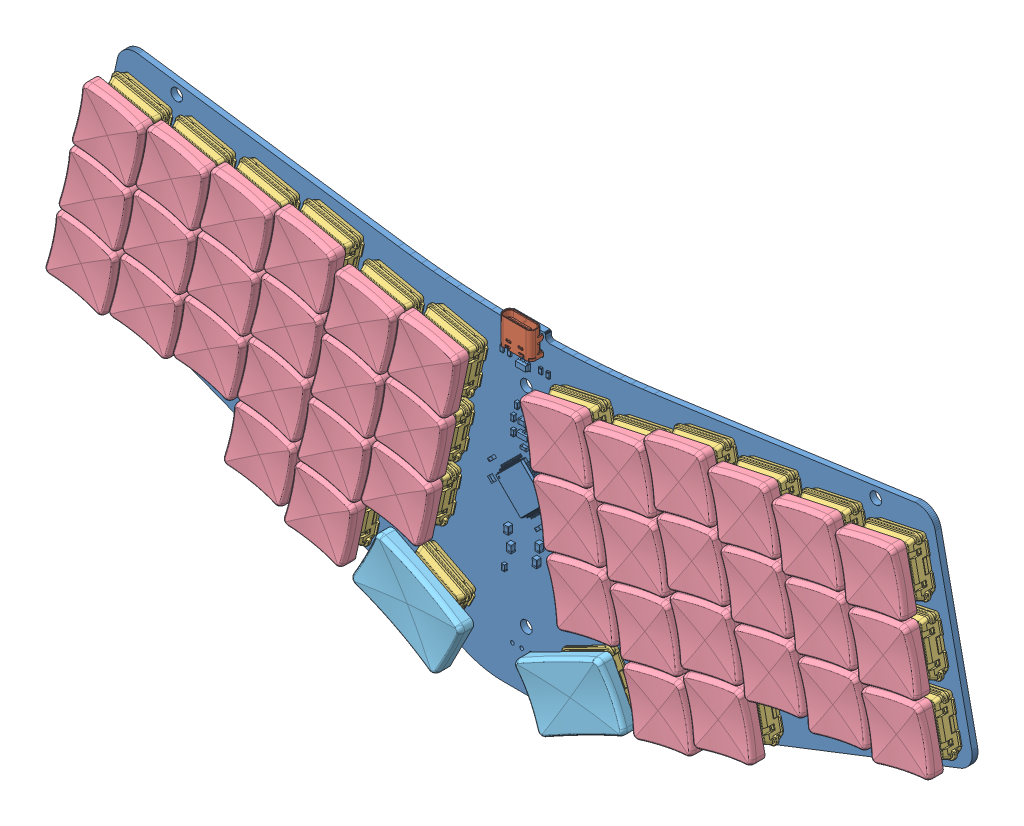
SolidWorks assembly pcb, configuration Default. Lengths in mm.
Overall size (242.52 98.19 15.02).
86 component instances, 5 part files, 216 mates.
Components (placement in the parent):
- pcb_base-1: pcb_base [Default] at (-103.1831 232.8514 177.6164) size (242.52 98.19 4.48)
- usb_c_connector-2: usb_c_connector [Default] at (101.2969 172.9514 179.2464) x (-1 0 0) z (0 0 1) size (8.95 7.9 4.2)
- kailh_choc_switch-1: kailh_choc_switch [Default] at (-6.8998 168.7135 181.3922) x (0.978148 -0.207912 0) z (0 0 1) size (15 15 11)
- kailh_choc_switch-2: kailh_choc_switch [Default] at (-10.4862 151.8404 181.3922) x (0.978148 -0.207912 0) z (0 0 1) size (15 15 11)
- kailh_choc_switch-3: kailh_choc_switch [Default] at (10.3891 167.0833 181.3922) x (0.978148 -0.207912 0) z (0 0 1) size (15 15 11)
- kailh_choc_switch-4: kailh_choc_switch [Default] at (6.8026 150.2102 181.3922) x (0.978148 -0.207912 0) z (0 0 1) size (15 15 11)
- kailh_choc_switch-5: kailh_choc_switch [Default] at (-14.0727 134.9674 181.3922) x (0.978148 -0.207912 0) z (0 0 1) size (15 15 11)
- kailh_choc_switch-6: kailh_choc_switch [Default] at (3.2162 133.3372 181.3922) x (0.978148 -0.207912 0) z (0 0 1) size (15 15 11)
- kailh_choc_switch-7: kailh_choc_switch [Default] at (27.7819 165.9422 181.3922) x (0.978148 -0.207912 0) z (0 0 1) size (15 15 11)
- kailh_choc_switch-8: kailh_choc_switch [Default] at (24.1955 149.0691 181.3922) x (0.978148 -0.207912 0) z (0 0 1) size (15 15 11)
- kailh_choc_switch-9: kailh_choc_switch [Default] at (20.609 132.1961 181.3922) x (0.978148 -0.207912 0) z (0 0 1) size (15 15 11)
- kailh_choc_switch-10: kailh_choc_switch [Default] at (34.4153 114.1819 181.3922) x (0.978148 -0.207912 0) z (0 0 1) size (15 15 11)
- kailh_choc_switch-11: kailh_choc_switch [Default] at (38.0018 131.055 181.3922) x (0.978148 -0.207912 0) z (0 0 1) size (15 15 11)
- kailh_choc_switch-12: kailh_choc_switch [Default] at (41.5883 147.928 181.3922) x (0.978148 -0.207912 0) z (0 0 1) size (15 15 11)
- kailh_choc_switch-13: kailh_choc_switch [Default] at (45.1748 164.8011 181.3922) x (0.978148 -0.207912 0) z (0 0 1) size (15 15 11)
- kailh_choc_switch-14: kailh_choc_switch [Default] at (50.7686 108.1501 181.3922) x (0.978148 -0.207912 0) z (0 0 1) size (15 15 11)
- kailh_choc_switch-15: kailh_choc_switch [Default] at (54.3551 125.0231 181.3922) x (0.978148 -0.207912 0) z (0 0 1) size (15 15 11)
- kailh_choc_switch-16: kailh_choc_switch [Default] at (57.9415 141.8962 181.3922) x (0.978148 -0.207912 0) z (0 0 1) size (15 15 11)
- kailh_choc_switch-17: kailh_choc_switch [Default] at (61.528 158.7692 181.3922) x (0.978148 -0.207912 0) z (0 0 1) size (15 15 11)
- kailh_choc_switch-18: kailh_choc_switch [Default] at (78.8169 157.139 181.3922) x (0.978148 -0.207912 0) z (0 0 1) size (15 15 11)
- kailh_choc_switch-19: kailh_choc_switch [Default] at (75.2304 140.266 181.3922) x (0.978148 -0.207912 0) z (0 0 1) size (15 15 11)
- kailh_choc_switch-20: kailh_choc_switch [Default] at (71.6439 123.3929 181.3922) x (0.978148 -0.207912 0) z (0 0 1) size (15 15 11)
- kailh_choc_switch-21: kailh_choc_switch [Default] at (74.6872 99.2323 181.3922) x (0.891007 -0.45399 0) z (0 0 1) size (15 15 11)
- kailh_choc_switch-22: kailh_choc_switch [Default] at (118.9466 99.2323 181.3922) x (0.891007 0.45399 0) z (0 0 1) size (15 15 11)
- kailh_choc_switch-23: kailh_choc_switch [Default] at (121.9898 123.3929 181.3922) x (0.978148 0.207912 0) z (0 0 1) size (15 15 11)
- kailh_choc_switch-24: kailh_choc_switch [Default] at (118.4034 140.266 181.3922) x (0.978148 0.207912 0) z (0 0 1) size (15 15 11)
- kailh_choc_switch-25: kailh_choc_switch [Default] at (114.8169 157.139 181.3922) x (0.978148 0.207912 0) z (0 0 1) size (15 15 11)
- kailh_choc_switch-26: kailh_choc_switch [Default] at (142.8652 108.1501 181.3922) x (0.978148 0.207912 0) z (0 0 1) size (15 15 11)
- kailh_choc_switch-27: kailh_choc_switch [Default] at (139.2787 125.0231 181.3922) x (0.978148 0.207912 0) z (0 0 1) size (15 15 11)
- kailh_choc_switch-28: kailh_choc_switch [Default] at (135.6922 141.8962 181.3922) x (0.978148 0.207912 0) z (0 0 1) size (15 15 11)
- kailh_choc_switch-29: kailh_choc_switch [Default] at (132.1058 158.7692 181.3922) x (0.978148 0.207912 0) z (0 0 1) size (15 15 11)
- kailh_choc_switch-30: kailh_choc_switch [Default] at (159.2185 114.1819 181.3922) x (0.978148 0.207912 0) z (0 0 1) size (15 15 11)
- kailh_choc_switch-31: kailh_choc_switch [Default] at (155.632 131.055 181.3922) x (0.978148 0.207912 0) z (0 0 1) size (15 15 11)
- kailh_choc_switch-32: kailh_choc_switch [Default] at (152.0455 147.928 181.3922) x (0.978148 0.207912 0) z (0 0 1) size (15 15 11)
- kailh_choc_switch-33: kailh_choc_switch [Default] at (148.459 164.8011 181.3922) x (0.978148 0.207912 0) z (0 0 1) size (15 15 11)
- kailh_choc_switch-34: kailh_choc_switch [Default] at (173.0248 132.1961 181.3922) x (0.978148 0.207912 0) z (0 0 1) size (15 15 11)
- kailh_choc_switch-35: kailh_choc_switch [Default] at (169.4383 149.0691 181.3922) x (0.978148 0.207912 0) z (0 0 1) size (15 15 11)
- kailh_choc_switch-36: kailh_choc_switch [Default] at (165.8519 165.9422 181.3922) x (0.978148 0.207912 0) z (0 0 1) size (15 15 11)
- kailh_choc_switch-37: kailh_choc_switch [Default] at (190.4176 133.3372 181.3922) x (0.978148 0.207912 0) z (0 0 1) size (15 15 11)
- kailh_choc_switch-38: kailh_choc_switch [Default] at (186.8312 150.2102 181.3922) x (0.978148 0.207912 0) z (0 0 1) size (15 15 11)
- kailh_choc_switch-39: kailh_choc_switch [Default] at (183.2447 167.0833 181.3922) x (0.978148 0.207912 0) z (0 0 1) size (15 15 11)
- kailh_choc_switch-40: kailh_choc_switch [Default] at (207.7065 134.9674 181.3922) x (0.978148 0.207912 0) z (0 0 1) size (15 15 11)
- kailh_choc_switch-41: kailh_choc_switch [Default] at (204.12 151.8404 181.3922) x (0.978148 0.207912 0) z (0 0 1) size (15 15 11)
- kailh_choc_switch-42: kailh_choc_switch [Default] at (200.5336 168.7135 181.3922) x (0.978148 0.207912 0) z (0 0 1) size (15 15 11)
- 1U-keycap-1: 1U-keycap [Default] at (-16.6848 162.359 186.1922) x (0.978148 -0.207912 0) z (-0.207912 -0.978148 0) size (16.7 6.52 16.7)
- 1U-keycap-2: 1U-keycap [Default] at (-20.2712 145.486 186.1922) x (0.978148 -0.207912 0) z (-0.207912 -0.978148 0) size (16.7 6.52 16.7)
- 1U-keycap-3: 1U-keycap [Default] at (-23.8577 128.6129 186.1922) x (0.978148 -0.207912 0) z (-0.207912 -0.978148 0) size (16.7 6.52 16.7)
- 1U-keycap-4: 1U-keycap [Default] at (0.6041 160.7288 186.1922) x (0.978148 -0.207912 0) z (-0.207912 -0.978148 0) size (16.7 6.52 16.7)
- 1.5U-keycap-1: 1.5U-keycap [Default] at (59.3586 97.7833 186.1922) x (0.891007 -0.45399 0) z (-0.45399 -0.891007 0) size (26.46 7.52 16.96)
- 1U-keycap-5: 1U-keycap [Default] at (40.9836 101.7956 186.1922) x (0.978148 -0.207912 0) z (-0.207912 -0.978148 0) size (16.7 6.52 16.7)
- 1U-keycap-6: 1U-keycap [Default] at (24.6303 107.8275 186.1922) x (0.978148 -0.207912 0) z (-0.207912 -0.978148 0) size (16.7 6.52 16.7)
- 1U-keycap-7: 1U-keycap [Default] at (44.5701 118.6687 186.1922) x (0.978148 -0.207912 0) z (-0.207912 -0.978148 0) size (16.7 6.52 16.7)
- 1U-keycap-8: 1U-keycap [Default] at (61.859 117.0385 186.1922) x (0.978148 -0.207912 0) z (-0.207912 -0.978148 0) size (16.7 6.52 16.7)
- 1U-keycap-9: 1U-keycap [Default] at (69.0319 150.7846 186.1922) x (0.978148 -0.207912 0) z (-0.207912 -0.978148 0) size (16.7 6.52 16.7)
- 1U-keycap-10: 1U-keycap [Default] at (31.8033 141.5736 186.1922) x (0.978148 -0.207912 0) z (-0.207912 -0.978148 0) size (16.7 6.52 16.7)
- 1.5U-keycap-2: 1.5U-keycap [Default] at (111.109 85.9796 186.1922) x (0.891007 0.45399 0) z (0.45399 -0.891007 0) size (26.46 7.52 16.96)
- 1U-keycap-11: 1U-keycap [Default] at (136.5107 98.3651 186.1922) x (0.978148 0.207912 0) z (0.207912 -0.978148 0) size (16.7 6.52 16.7)
- 1U-keycap-14: 1U-keycap [Default] at (108.4624 147.3541 186.1922) x (0.978148 0.207912 0) z (0.207912 -0.978148 0) size (16.7 6.52 16.7)
- 1U-keycap-15: 1U-keycap [Default] at (194.1791 158.9285 186.1922) x (0.978148 0.207912 0) z (0.207912 -0.978148 0) size (16.7 6.52 16.7)
- 1U-keycap-16: 1U-keycap [Default] at (201.3521 125.1824 186.1922) x (0.978148 0.207912 0) z (0.207912 -0.978148 0) size (16.7 6.52 16.7)
- 1U-keycap-17: 1U-keycap [Default] at (166.6704 122.4111 186.1922) x (0.978148 0.207912 0) z (0.207912 -0.978148 0) size (16.7 6.52 16.7)
- 1U-keycap-18: 1U-keycap [Default] at (-2.9824 143.8558 186.1922) x (0.978148 -0.207912 0) z (-0.207912 -0.978148 0) size (16.7 6.52 16.7)
- 1U-keycap-19: 1U-keycap [Default] at (-6.5688 126.9827 186.1922) x (0.978148 -0.207912 0) z (-0.207912 -0.978148 0) size (16.7 6.52 16.7)
- 1U-keycap-20: 1U-keycap [Default] at (17.9969 159.5877 186.1922) x (0.978148 -0.207912 0) z (-0.207912 -0.978148 0) size (16.7 6.52 16.7)
- 1U-keycap-21: 1U-keycap [Default] at (14.4105 142.7147 186.1922) x (0.978148 -0.207912 0) z (-0.207912 -0.978148 0) size (16.7 6.52 16.7)
- 1U-keycap-22: 1U-keycap [Default] at (10.824 125.8416 186.1922) x (0.978148 -0.207912 0) z (-0.207912 -0.978148 0) size (16.7 6.52 16.7)
- 1U-keycap-23: 1U-keycap [Default] at (28.2168 124.7005 186.1922) x (0.978148 -0.207912 0) z (-0.207912 -0.978148 0) size (16.7 6.52 16.7)
- 1U-keycap-24: 1U-keycap [Default] at (35.3898 158.4466 186.1922) x (0.978148 -0.207912 0) z (-0.207912 -0.978148 0) size (16.7 6.52 16.7)
- 1U-keycap-25: 1U-keycap [Default] at (51.743 152.4148 186.1922) x (0.978148 -0.207912 0) z (-0.207912 -0.978148 0) size (16.7 6.52 16.7)
- 1U-keycap-26: 1U-keycap [Default] at (48.1566 135.5417 186.1922) x (0.978148 -0.207912 0) z (-0.207912 -0.978148 0) size (16.7 6.52 16.7)
- 1U-keycap-27: 1U-keycap [Default] at (65.4454 133.9115 186.1922) x (0.978148 -0.207912 0) z (-0.207912 -0.978148 0) size (16.7 6.52 16.7)
- 1U-keycap-28: 1U-keycap [Default] at (112.0489 130.481 186.1922) x (0.978148 0.207912 0) z (0.207912 -0.978148 0) size (16.7 6.52 16.7)
- 1U-keycap-29: 1U-keycap [Default] at (115.6354 113.608 186.1922) x (0.978148 0.207912 0) z (0.207912 -0.978148 0) size (16.7 6.52 16.7)
- 1U-keycap-30: 1U-keycap [Default] at (125.7513 148.9842 186.1922) x (0.978148 0.207912 0) z (0.207912 -0.978148 0) size (16.7 6.52 16.7)
- 1U-keycap-31: 1U-keycap [Default] at (129.3378 132.1112 186.1922) x (0.978148 0.207912 0) z (0.207912 -0.978148 0) size (16.7 6.52 16.7)
- 1U-keycap-32: 1U-keycap [Default] at (132.9243 115.2381 186.1922) x (0.978148 0.207912 0) z (0.207912 -0.978148 0) size (16.7 6.52 16.7)
- 1U-keycap-33: 1U-keycap [Default] at (142.1046 155.0161 186.1922) x (0.978148 0.207912 0) z (0.207912 -0.978148 0) size (16.7 6.52 16.7)
- 1U-keycap-34: 1U-keycap [Default] at (145.6911 138.143 186.1922) x (0.978148 0.207912 0) z (0.207912 -0.978148 0) size (16.7 6.52 16.7)
- 1U-keycap-35: 1U-keycap [Default] at (149.2775 121.27 186.1922) x (0.978148 0.207912 0) z (0.207912 -0.978148 0) size (16.7 6.52 16.7)
- 1U-keycap-36: 1U-keycap [Default] at (152.864 104.3969 186.1922) x (0.978148 0.207912 0) z (0.207912 -0.978148 0) size (16.7 6.52 16.7)
- 1U-keycap-37: 1U-keycap [Default] at (159.4974 156.1572 186.1922) x (0.978148 0.207912 0) z (0.207912 -0.978148 0) size (16.7 6.52 16.7)
- 1U-keycap-38: 1U-keycap [Default] at (163.0839 139.2841 186.1922) x (0.978148 0.207912 0) z (0.207912 -0.978148 0) size (16.7 6.52 16.7)
- 1U-keycap-39: 1U-keycap [Default] at (184.0632 123.5522 186.1922) x (0.978148 0.207912 0) z (0.207912 -0.978148 0) size (16.7 6.52 16.7)
- 1U-keycap-40: 1U-keycap [Default] at (180.4767 140.4252 186.1922) x (0.978148 0.207912 0) z (0.207912 -0.978148 0) size (16.7 6.52 16.7)
- 1U-keycap-41: 1U-keycap [Default] at (176.8902 157.2983 186.1922) x (0.978148 0.207912 0) z (0.207912 -0.978148 0) size (16.7 6.52 16.7)
- 1U-keycap-42: 1U-keycap [Default] at (197.7656 142.0554 186.1922) x (0.978148 0.207912 0) z (0.207912 -0.978148 0) size (16.7 6.52 16.7)
Mates (geometry in assembly coordinates):
- Concentric8: concentric aligned: cylinder of pcb_base-1 through (99.7169 166.7014 176.8264) axis (0 0 1) radius 0.325; cylinder of usb_c_connector-2 through (99.7169 166.7014 179.2464) axis (0 0 1) radius 0.25
- Coincident1: coincident anti-aligned: plane of pcb_base-1 through (96.8169 139.9659 179.1964) normal (0 0 1); plane of usb_c_connector-2 through (94.4769 165.5464 179.1964) normal (0 0 -1)
- Concentric17: concentric anti-aligned: circle of pcb_base-1; circle of kailh_choc_switch-1
- Coincident11: coincident anti-aligned: plane of pcb_base-1 through (96.8169 139.9659 179.1964) normal (0 0 1); plane of kailh_choc_switch-1 through (-1.5081 163.6607 179.1964) normal (0 0 -1)
- Concentric24: concentric: circle of pcb_base-1; circle of kailh_choc_switch-2
- Coincident12: coincident: plane of pcb_base-1 through (96.8169 139.9659 179.1964) normal (0 0 1); plane of kailh_choc_switch-2 through (-5.0946 146.7877 179.1964) normal (0 0 -1)
- Concentric25: concentric anti-aligned: circle of pcb_base-1; circle of kailh_choc_switch-3
- Coincident13: coincident anti-aligned: plane of pcb_base-1 through (96.8169 139.9659 179.1964) normal (0 0 1); plane of kailh_choc_switch-3 through (15.7807 162.0306 179.1964) normal (0 0 -1)
- Concentric26: concentric: circle of pcb_base-1; circle of kailh_choc_switch-4
- Coincident15: coincident: plane of pcb_base-1 through (96.8169 139.9659 179.1964) normal (0 0 1); plane of kailh_choc_switch-4 through (12.1943 145.1575 179.1964) normal (0 0 -1)
- Angle1: planar angle = 0.20944 rad aligned: plane of kailh_choc_switch-1 through (-1.5741 169.8848 186.9922) normal (0.207912 0.978148 0); plane of pcb_base-1 through (92.0669 171.5153 177.6164) normal (0 1 0)
- Angle2: planar angle = 0.20944 rad aligned: plane of kailh_choc_switch-2 through (-5.1606 153.0118 186.9922) normal (0.207912 0.978148 0); plane of pcb_base-1 through (92.0669 171.5153 177.6164) normal (0 1 0)
- Angle3: planar angle = 0.20944 rad aligned: plane of kailh_choc_switch-3 through (15.7148 168.2547 186.9922) normal (0.207912 0.978148 0); plane of pcb_base-1 through (92.0669 171.5153 177.6164) normal (0 1 0)
- Angle4: planar angle = 0.20944 rad aligned: plane of kailh_choc_switch-4 through (12.1283 151.3816 186.9922) normal (0.207912 0.978148 0); plane of pcb_base-1 through (92.0669 171.5153 177.6164) normal (0 1 0)
- Concentric27: concentric anti-aligned: cylinder of pcb_base-1 through (-14.0727 134.9674 176.8264) axis (0 0 1) radius 1.7145; circle of kailh_choc_switch-5
- Coincident20: coincident anti-aligned: plane of pcb_base-1 through (96.8169 139.9659 179.1964) normal (0 0 1); plane of kailh_choc_switch-5 through (-8.6811 129.9146 179.1964) normal (0 0 -1)
- Angle5: planar angle = 0.20944 rad aligned: plane of kailh_choc_switch-5 through (-8.747 136.1387 186.9922) normal (0.207912 0.978148 0); plane of pcb_base-1 through (92.0669 171.5153 177.6164) normal (0 1 0)
- Concentric28: concentric anti-aligned: cylinder of pcb_base-1 through (3.2162 133.3372 176.8264) axis (0 0 1) radius 1.7145; circle of kailh_choc_switch-6
- Concentric29: concentric anti-aligned: cylinder of pcb_base-1 through (20.609 132.1961 176.8264) axis (0 0 1) radius 1.7145; circle of kailh_choc_switch-9
- Concentric30: concentric anti-aligned: cylinder of pcb_base-1 through (24.1955 149.0691 176.8264) axis (0 0 1) radius 1.7145; circle of kailh_choc_switch-8
- Concentric31: concentric: cylinder of pcb_base-1 through (27.7819 165.9422 176.8264) axis (0 0 1) radius 1.7145; circle of kailh_choc_switch-7
- Coincident22: coincident anti-aligned: plane of pcb_base-1 through (96.8169 139.9659 179.1964) normal (0 0 1); plane of kailh_choc_switch-6 through (8.6078 128.2845 179.1964) normal (0 0 -1)
- Coincident23: coincident anti-aligned: plane of pcb_base-1 through (96.8169 139.9659 179.1964) normal (0 0 1); plane of kailh_choc_switch-9 through (26.0006 127.1434 179.1964) normal (0 0 -1)
- Coincident24: coincident anti-aligned: plane of pcb_base-1 through (96.8169 139.9659 179.1964) normal (0 0 1); plane of kailh_choc_switch-8 through (29.5871 144.0164 179.1964) normal (0 0 -1)
- Coincident25: coincident: plane of pcb_base-1 through (96.8169 139.9659 179.1964) normal (0 0 1); plane of kailh_choc_switch-7 through (33.1736 160.8894 179.1964) normal (0 0 -1)
- Angle6: planar angle = 0.20944 rad aligned: plane of kailh_choc_switch-6 through (8.5418 134.5086 186.9922) normal (0.207912 0.978148 0); plane of pcb_base-1 through (92.0669 171.5153 177.6164) normal (0 1 0)
- Angle7: planar angle = 0.20944 rad aligned: plane of kailh_choc_switch-9 through (25.9347 133.3675 186.9922) normal (0.207912 0.978148 0); plane of pcb_base-1 through (92.0669 171.5153 177.6164) normal (0 1 0)
- Angle8: planar angle = 0.20944 rad aligned: plane of kailh_choc_switch-8 through (29.5211 150.2405 186.9922) normal (0.207912 0.978148 0); plane of pcb_base-1 through (92.0669 171.5153 177.6164) normal (0 1 0)
- Angle9: planar angle = 0.20944 rad aligned: plane of kailh_choc_switch-7 through (33.1076 167.1135 186.9922) normal (0.207912 0.978148 0); plane of pcb_base-1 through (92.0669 171.5153 177.6164) normal (0 1 0)
- Concentric32: concentric anti-aligned: cylinder of pcb_base-1 through (34.4153 114.1819 176.8264) axis (0 0 1) radius 1.7145; circle of kailh_choc_switch-10
- Concentric33: concentric anti-aligned: cylinder of pcb_base-1 through (38.0018 131.055 176.8264) axis (0 0 1) radius 1.7145; circle of kailh_choc_switch-11
- Concentric34: concentric anti-aligned: cylinder of pcb_base-1 through (41.5883 147.928 176.8264) axis (0 0 1) radius 1.7145; circle of kailh_choc_switch-12
- Concentric35: concentric: cylinder of pcb_base-1 through (45.1748 164.8011 176.8264) axis (0 0 1) radius 1.7145; circle of kailh_choc_switch-13
- Coincident30: coincident anti-aligned: plane of pcb_base-1 through (96.8169 139.9659 179.1964) normal (0 0 1); plane of kailh_choc_switch-10 through (39.807 109.1292 179.1964) normal (0 0 -1)
- Coincident31: coincident anti-aligned: plane of pcb_base-1 through (96.8169 139.9659 179.1964) normal (0 0 1); plane of kailh_choc_switch-11 through (43.3934 126.0022 179.1964) normal (0 0 -1)
- Coincident32: coincident anti-aligned: plane of pcb_base-1 through (96.8169 139.9659 179.1964) normal (0 0 1); plane of kailh_choc_switch-12 through (46.9799 142.8753 179.1964) normal (0 0 -1)
- Coincident33: coincident: plane of pcb_base-1 through (96.8169 139.9659 179.1964) normal (0 0 1); plane of kailh_choc_switch-13 through (50.5664 159.7483 179.1964) normal (0 0 -1)
- Angle10: planar angle = 0.20944 rad aligned: plane of kailh_choc_switch-10 through (39.741 115.3533 186.9922) normal (0.207912 0.978148 0); plane of pcb_base-1 through (92.0669 171.5153 177.6164) normal (0 1 0)
- Angle11: planar angle = 0.20944 rad aligned: plane of kailh_choc_switch-11 through (43.3275 132.2263 186.9922) normal (0.207912 0.978148 0); plane of pcb_base-1 through (92.0669 171.5153 177.6164) normal (0 1 0)
- Angle12: planar angle = 0.20944 rad aligned: plane of kailh_choc_switch-12 through (46.914 149.0994 186.9922) normal (0.207912 0.978148 0); plane of pcb_base-1 through (92.0669 171.5153 177.6164) normal (0 1 0)
- Angle13: planar angle = 0.20944 rad aligned: plane of kailh_choc_switch-13 through (50.5004 165.9724 186.9922) normal (0.207912 0.978148 0); plane of pcb_base-1 through (92.0669 171.5153 177.6164) normal (0 1 0)
- Concentric36: concentric anti-aligned: cylinder of pcb_base-1 through (50.7686 108.1501 176.8264) axis (0 0 1) radius 1.7145; circle of kailh_choc_switch-14
- Concentric37: concentric anti-aligned: cylinder of pcb_base-1 through (54.3551 125.0231 176.8264) axis (0 0 1) radius 1.7145; circle of kailh_choc_switch-15
- Concentric38: concentric anti-aligned: cylinder of pcb_base-1 through (57.9415 141.8962 176.8264) axis (0 0 1) radius 1.7145; circle of kailh_choc_switch-16
- Concentric39: concentric: cylinder of pcb_base-1 through (61.528 158.7692 176.8264) axis (0 0 1) radius 1.7145; circle of kailh_choc_switch-17
- Coincident38: coincident anti-aligned: plane of pcb_base-1 through (96.8169 139.9659 179.1964) normal (0 0 1); plane of kailh_choc_switch-14 through (56.1602 103.0974 179.1964) normal (0 0 -1)
- Coincident39: coincident anti-aligned: plane of pcb_base-1 through (96.8169 139.9659 179.1964) normal (0 0 1); plane of kailh_choc_switch-15 through (59.7467 119.9704 179.1964) normal (0 0 -1)
- Coincident40: coincident anti-aligned: plane of pcb_base-1 through (96.8169 139.9659 179.1964) normal (0 0 1); plane of kailh_choc_switch-16 through (63.3332 136.8434 179.1964) normal (0 0 -1)
- Coincident41: coincident: plane of pcb_base-1 through (96.8169 139.9659 179.1964) normal (0 0 1); plane of kailh_choc_switch-17 through (66.9197 153.7165 179.1964) normal (0 0 -1)
- Angle14: planar angle = 0.20944 rad aligned: plane of kailh_choc_switch-14 through (56.0943 109.3215 186.9922) normal (0.207912 0.978148 0); plane of pcb_base-1 through (92.0669 171.5153 177.6164) normal (0 1 0)
- Angle15: planar angle = 0.20944 rad aligned: plane of kailh_choc_switch-15 through (59.6808 126.1945 186.9922) normal (0.207912 0.978148 0); plane of pcb_base-1 through (92.0669 171.5153 177.6164) normal (0 1 0)
- Angle16: planar angle = 0.20944 rad aligned: plane of kailh_choc_switch-16 through (63.2672 143.0675 186.9922) normal (0.207912 0.978148 0); plane of pcb_base-1 through (92.0669 171.5153 177.6164) normal (0 1 0)
- Angle17: planar angle = 0.20944 rad aligned: plane of kailh_choc_switch-17 through (66.8537 159.9406 186.9922) normal (0.207912 0.978148 0); plane of pcb_base-1 through (92.0669 171.5153 177.6164) normal (0 1 0)
- Concentric40: concentric anti-aligned: cylinder of pcb_base-1 through (78.8169 157.139 176.8264) axis (0 0 1) radius 1.7145; circle of kailh_choc_switch-18
- Concentric41: concentric anti-aligned: cylinder of pcb_base-1 through (75.2304 140.266 176.8264) axis (0 0 1) radius 1.7145; circle of kailh_choc_switch-19
- Concentric42: concentric anti-aligned: cylinder of pcb_base-1 through (71.6439 123.3929 176.8264) axis (0 0 1) radius 1.7145; circle of kailh_choc_switch-20
- Concentric43: concentric: cylinder of pcb_base-1 through (74.6872 99.2323 176.8264) axis (0 0 1) radius 1.7145; circle of kailh_choc_switch-21
- Coincident46: coincident: plane of pcb_base-1 through (96.8169 139.9659 179.1964) normal (0 0 1); plane of kailh_choc_switch-21 through (78.5873 92.9562 179.1964) normal (0 0 -1)
- Coincident47: coincident anti-aligned: plane of pcb_base-1 through (96.8169 139.9659 179.1964) normal (0 0 1); plane of kailh_choc_switch-20 through (77.0356 118.3402 179.1964) normal (0 0 -1)
- Coincident48: coincident anti-aligned: plane of pcb_base-1 through (96.8169 139.9659 179.1964) normal (0 0 1); plane of kailh_choc_switch-19 through (80.6221 135.2133 179.1964) normal (0 0 -1)
- Coincident49: coincident anti-aligned: plane of pcb_base-1 through (96.8169 139.9659 179.1964) normal (0 0 1); plane of kailh_choc_switch-18 through (84.2085 152.0863 179.1964) normal (0 0 -1)
- Angle18: planar angle = 0.20944 rad aligned: plane of kailh_choc_switch-18 through (84.1426 158.3104 186.9922) normal (0.207912 0.978148 0); plane of pcb_base-1 through (92.0669 171.5153 177.6164) normal (0 1 0)
- Angle19: planar angle = 0.20944 rad aligned: plane of kailh_choc_switch-19 through (80.5561 141.4374 186.9922) normal (0.207912 0.978148 0); plane of pcb_base-1 through (92.0669 171.5153 177.6164) normal (0 1 0)
- Angle20: planar angle = 0.20944 rad aligned: plane of kailh_choc_switch-20 through (76.9696 124.5643 186.9922) normal (0.207912 0.978148 0); plane of pcb_base-1 through (92.0669 171.5153 177.6164) normal (0 1 0)
- Angle21: planar angle = 0.471239 rad aligned: plane of kailh_choc_switch-21 through (80.1345 98.9853 186.9922) normal (0.45399 0.891007 0); plane of pcb_base-1 through (92.0669 171.5153 177.6164) normal (0 1 0)
- Concentric44: concentric anti-aligned: cylinder of pcb_base-1 through (118.9466 99.2323 176.8264) axis (0 0 1) radius 1.7145; circle of kailh_choc_switch-22
- Concentric45: concentric anti-aligned: cylinder of pcb_base-1 through (121.9898 123.3929 176.8264) axis (0 0 1) radius 1.7145; circle of kailh_choc_switch-23
- Concentric46: concentric anti-aligned: cylinder of pcb_base-1 through (118.4034 140.266 176.8264) axis (0 0 1) radius 1.7145; circle of kailh_choc_switch-24
- Concentric47: concentric: cylinder of pcb_base-1 through (114.8169 157.139 176.8264) axis (0 0 1) radius 1.7145; circle of kailh_choc_switch-25
- Coincident54: coincident anti-aligned: plane of pcb_base-1 through (96.8169 139.9659 179.1964) normal (0 0 1); plane of kailh_choc_switch-22 through (126.3165 98.6986 179.1964) normal (0 0 -1)
- Coincident55: coincident anti-aligned: plane of pcb_base-1 through (96.8169 139.9659 179.1964) normal (0 0 1); plane of kailh_choc_switch-23 through (128.9705 120.97 179.1964) normal (0 0 -1)
- Coincident56: coincident anti-aligned: plane of pcb_base-1 through (96.8169 139.9659 179.1964) normal (0 0 1); plane of kailh_choc_switch-24 through (125.384 137.8431 179.1964) normal (0 0 -1)
- Coincident57: coincident: plane of pcb_base-1 through (96.8169 139.9659 179.1964) normal (0 0 1); plane of kailh_choc_switch-25 through (121.7975 154.7161 179.1964) normal (0 0 -1)
- Angle22: planar angle = 5.811946 rad aligned: plane of kailh_choc_switch-22 through (122.3483 103.4941 186.9922) normal (-0.45399 0.891007 0); plane of pcb_base-1 through (96.8169 171.5153 177.6164) normal (0 1 0)
- Angle23: planar angle = 6.073746 rad aligned: plane of kailh_choc_switch-23 through (126.3787 126.6292 186.9922) normal (-0.207912 0.978148 0); plane of pcb_base-1 through (96.8169 171.5153 177.6164) normal (0 1 0)
- Angle24: planar angle = 6.073746 rad aligned: plane of kailh_choc_switch-24 through (122.7922 143.5022 186.9922) normal (-0.207912 0.978148 0); plane of pcb_base-1 through (96.8169 171.5153 177.6164) normal (0 1 0)
- Angle25: planar angle = 6.073746 rad aligned: plane of kailh_choc_switch-25 through (119.2057 160.3753 186.9922) normal (-0.207912 0.978148 0); plane of pcb_base-1 through (96.8169 171.5153 177.6164) normal (0 1 0)
- Concentric48: concentric: cylinder of pcb_base-1 through (142.8652 108.1501 176.8264) axis (0 0 1) radius 1.7145; circle of kailh_choc_switch-26
- Concentric49: concentric anti-aligned: cylinder of pcb_base-1 through (139.2787 125.0231 176.8264) axis (0 0 1) radius 1.7145; circle of kailh_choc_switch-27
- Concentric50: concentric anti-aligned: cylinder of pcb_base-1 through (135.6922 141.8962 176.8264) axis (0 0 1) radius 1.7145; circle of kailh_choc_switch-28
- Concentric51: concentric anti-aligned: cylinder of pcb_base-1 through (132.1058 158.7692 176.8264) axis (0 0 1) radius 1.7145; circle of kailh_choc_switch-29
- Coincident62: coincident: plane of pcb_base-1 through (96.8169 139.9659 179.1964) normal (0 0 1); plane of kailh_choc_switch-26 through (149.8458 105.7272 179.1964) normal (0 0 -1)
- Coincident63: coincident anti-aligned: plane of pcb_base-1 through (96.8169 139.9659 179.1964) normal (0 0 1); plane of kailh_choc_switch-27 through (146.2594 122.6002 179.1964) normal (0 0 -1)
- Coincident64: coincident anti-aligned: plane of pcb_base-1 through (96.8169 139.9659 179.1964) normal (0 0 1); plane of kailh_choc_switch-28 through (142.6729 139.4733 179.1964) normal (0 0 -1)
- Coincident65: coincident anti-aligned: plane of pcb_base-1 through (96.8169 139.9659 179.1964) normal (0 0 1); plane of kailh_choc_switch-29 through (139.0864 156.3463 179.1964) normal (0 0 -1)
- Angle26: planar angle = 0.20944 rad aligned: plane of kailh_choc_switch-29 through (136.4946 162.0055 186.9922) normal (-0.207912 0.978148 0); plane of pcb_base-1 through (96.8169 171.5153 177.6164) normal (0 1 0)
- Angle27: planar angle = 0.20944 rad aligned: plane of kailh_choc_switch-28 through (140.0811 145.1324 186.9922) normal (-0.207912 0.978148 0); plane of pcb_base-1 through (96.8169 171.5153 177.6164) normal (0 1 0)
- Angle28: planar angle = 0.20944 rad aligned: plane of kailh_choc_switch-27 through (143.6675 128.2594 186.9922) normal (-0.207912 0.978148 0); plane of pcb_base-1 through (96.8169 171.5153 177.6164) normal (0 1 0)
- Angle29: planar angle = 0.20944 rad aligned: plane of kailh_choc_switch-26 through (147.254 111.3863 186.9922) normal (-0.207912 0.978148 0); plane of pcb_base-1 through (96.8169 171.5153 177.6164) normal (0 1 0)
- Concentric52: concentric anti-aligned: cylinder of pcb_base-1 through (159.2185 114.1819 176.8264) axis (0 0 1) radius 1.7145; circle of kailh_choc_switch-30
- Concentric53: concentric anti-aligned: cylinder of pcb_base-1 through (155.632 131.055 176.8264) axis (0 0 1) radius 1.7145; circle of kailh_choc_switch-31
- Concentric54: concentric anti-aligned: cylinder of pcb_base-1 through (152.0455 147.928 176.8264) axis (0 0 1) radius 1.7145; circle of kailh_choc_switch-32
- Concentric55: concentric: cylinder of pcb_base-1 through (148.459 164.8011 176.8264) axis (0 0 1) radius 1.7145; circle of kailh_choc_switch-33
- Coincident70: coincident anti-aligned: plane of pcb_base-1 through (96.8169 139.9659 179.1964) normal (0 0 1); plane of kailh_choc_switch-30 through (166.1991 111.759 179.1964) normal (0 0 -1)
- Coincident71: coincident anti-aligned: plane of pcb_base-1 through (96.8169 139.9659 179.1964) normal (0 0 1); plane of kailh_choc_switch-31 through (162.6126 128.6321 179.1964) normal (0 0 -1)
- Coincident72: coincident anti-aligned: plane of pcb_base-1 through (96.8169 139.9659 179.1964) normal (0 0 1); plane of kailh_choc_switch-32 through (159.0261 145.5051 179.1964) normal (0 0 -1)
- Coincident73: coincident: plane of pcb_base-1 through (96.8169 139.9659 179.1964) normal (0 0 1); plane of kailh_choc_switch-33 through (155.4397 162.3781 179.1964) normal (0 0 -1)
- Angle30: planar angle = 0.20944 rad aligned: plane of kailh_choc_switch-30 through (163.6073 117.4182 186.9922) normal (-0.207912 0.978148 0); plane of pcb_base-1 through (96.8169 171.5153 177.6164) normal (0 1 0)
- Angle31: planar angle = 0.20944 rad aligned: plane of kailh_choc_switch-31 through (160.0208 134.2912 186.9922) normal (-0.207912 0.978148 0); plane of pcb_base-1 through (96.8169 171.5153 177.6164) normal (0 1 0)
- Angle32: planar angle = 0.20944 rad aligned: plane of kailh_choc_switch-32 through (156.4343 151.1643 186.9922) normal (-0.207912 0.978148 0); plane of pcb_base-1 through (96.8169 171.5153 177.6164) normal (0 1 0)
- Angle33: planar angle = 0.20944 rad aligned: plane of kailh_choc_switch-33 through (152.8478 168.0373 186.9922) normal (-0.207912 0.978148 0); plane of pcb_base-1 through (96.8169 171.5153 177.6164) normal (0 1 0)
- Concentric56: concentric anti-aligned: cylinder of pcb_base-1 through (173.0248 132.1961 176.8264) axis (0 0 1) radius 1.7145; circle of kailh_choc_switch-34
- Concentric57: concentric anti-aligned: cylinder of pcb_base-1 through (169.4383 149.0691 176.8264) axis (0 0 1) radius 1.7145; circle of kailh_choc_switch-35
- Concentric58: concentric: cylinder of pcb_base-1 through (165.8519 165.9422 176.8264) axis (0 0 1) radius 1.7145; circle of kailh_choc_switch-36
- Coincident78: coincident anti-aligned: plane of pcb_base-1 through (96.8169 139.9659 179.1964) normal (0 0 1); plane of kailh_choc_switch-34 through (180.0054 129.7732 179.1964) normal (0 0 -1)
- Coincident79: coincident anti-aligned: plane of pcb_base-1 through (96.8169 139.9659 179.1964) normal (0 0 1); plane of kailh_choc_switch-35 through (176.419 146.6462 179.1964) normal (0 0 -1)
- Coincident80: coincident: plane of pcb_base-1 through (96.8169 139.9659 179.1964) normal (0 0 1); plane of kailh_choc_switch-36 through (172.8325 163.5193 179.1964) normal (0 0 -1)
- Angle34: planar angle = 0.20944 rad aligned: plane of kailh_choc_switch-34 through (177.4136 135.4323 186.9922) normal (-0.207912 0.978148 0); plane of pcb_base-1 through (96.8169 171.5153 177.6164) normal (0 1 0)
- Angle35: planar angle = 0.20944 rad aligned: plane of kailh_choc_switch-35 through (173.8271 152.3054 186.9922) normal (-0.207912 0.978148 0); plane of pcb_base-1 through (96.8169 171.5153 177.6164) normal (0 1 0)
- Angle36: planar angle = 0.20944 rad aligned: plane of kailh_choc_switch-36 through (170.2407 169.1784 186.9922) normal (-0.207912 0.978148 0); plane of pcb_base-1 through (96.8169 171.5153 177.6164) normal (0 1 0)
- Concentric59: concentric anti-aligned: cylinder of pcb_base-1 through (190.4176 133.3372 176.8264) axis (0 0 1) radius 1.7145; circle of kailh_choc_switch-37
- Concentric60: concentric anti-aligned: cylinder of pcb_base-1 through (186.8312 150.2102 176.8264) axis (0 0 1) radius 1.7145; circle of kailh_choc_switch-38
- Concentric61: concentric: cylinder of pcb_base-1 through (183.2447 167.0833 176.8264) axis (0 0 1) radius 1.7145; circle of kailh_choc_switch-39
- Coincident84: coincident anti-aligned: plane of pcb_base-1 through (96.8169 139.9659 179.1964) normal (0 0 1); plane of kailh_choc_switch-37 through (197.3983 130.9143 179.1964) normal (0 0 -1)
- Coincident85: coincident anti-aligned: plane of pcb_base-1 through (96.8169 139.9659 179.1964) normal (0 0 1); plane of kailh_choc_switch-38 through (193.8118 147.7873 179.1964) normal (0 0 -1)
- Coincident86: coincident: plane of pcb_base-1 through (96.8169 139.9659 179.1964) normal (0 0 1); plane of kailh_choc_switch-39 through (190.2253 164.6604 179.1964) normal (0 0 -1)
- Angle37: planar angle = 0.20944 rad aligned: plane of kailh_choc_switch-37 through (194.8065 136.5734 186.9922) normal (-0.207912 0.978148 0); plane of pcb_base-1 through (96.8169 171.5153 177.6164) normal (0 1 0)
- Angle38: planar angle = 0.20944 rad aligned: plane of kailh_choc_switch-38 through (191.22 153.4465 186.9922) normal (-0.207912 0.978148 0); plane of pcb_base-1 through (96.8169 171.5153 177.6164) normal (0 1 0)
- Angle39: planar angle = 0.20944 rad aligned: plane of kailh_choc_switch-39 through (187.6335 170.3195 186.9922) normal (-0.207912 0.978148 0); plane of pcb_base-1 through (96.8169 171.5153 177.6164) normal (0 1 0)
- Concentric62: concentric anti-aligned: cylinder of pcb_base-1 through (207.7065 134.9674 176.8264) axis (0 0 1) radius 1.7145; circle of kailh_choc_switch-40
- Concentric63: concentric anti-aligned: cylinder of pcb_base-1 through (204.12 151.8404 176.8264) axis (0 0 1) radius 1.7145; circle of kailh_choc_switch-41
- Concentric64: concentric: cylinder of pcb_base-1 through (200.5336 168.7135 176.8264) axis (0 0 1) radius 1.7145; circle of kailh_choc_switch-42
- Coincident90: coincident anti-aligned: plane of pcb_base-1 through (96.8169 139.9659 179.1964) normal (0 0 1); plane of kailh_choc_switch-40 through (214.6871 132.5445 179.1964) normal (0 0 -1)
- Coincident91: coincident anti-aligned: plane of pcb_base-1 through (96.8169 139.9659 179.1964) normal (0 0 1); plane of kailh_choc_switch-41 through (211.1007 149.4175 179.1964) normal (0 0 -1)
- Coincident92: coincident: plane of pcb_base-1 through (96.8169 139.9659 179.1964) normal (0 0 1); plane of kailh_choc_switch-42 through (207.5142 166.2905 179.1964) normal (0 0 -1)
- Angle40: planar angle = 0.20944 rad aligned: plane of kailh_choc_switch-40 through (212.0953 138.2036 186.9922) normal (-0.207912 0.978148 0); plane of pcb_base-1 through (96.8169 171.5153 177.6164) normal (0 1 0)
- Angle41: planar angle = 0.20944 rad aligned: plane of kailh_choc_switch-41 through (208.5088 155.0767 186.9922) normal (-0.207912 0.978148 0); plane of pcb_base-1 through (96.8169 171.5153 177.6164) normal (0 1 0)
- Angle42: planar angle = 0.20944 rad aligned: plane of kailh_choc_switch-42 through (204.9224 171.9497 186.9922) normal (-0.207912 0.978148 0); plane of pcb_base-1 through (96.8169 171.5153 177.6164) normal (0 1 0)
- Concentric65: concentric aligned: circle of kailh_choc_switch-1; circle of keycaps-1
- Coincident93: coincident anti-aligned: plane of kailh_choc_switch-1 through (-12.4244 166.606 187.1922) normal (0 0 1); plane of keycaps-1 through (-16.6848 162.359 187.1922) normal (0 0 -1)
- Angle43: planar angle = 2.932153 rad anti-aligned: plane of keycaps-1 through (1.418 175.3798 190.1922) normal (0.207912 0.978148 0); plane of pcb_base-1 through (92.0669 171.5153 177.6164) normal (0 1 0)
- Concentric66: concentric aligned: circle of kailh_choc_switch-2; circle of keycaps-2
- Coincident95: coincident anti-aligned: plane of kailh_choc_switch-2 through (-16.0109 149.733 187.1922) normal (0 0 1); plane of keycaps-2 through (-20.2712 145.486 187.1922) normal (0 0 -1)
- Coincident96: coincident anti-aligned: plane of kailh_choc_switch-5 through (-19.5974 132.8599 187.1922) normal (0 0 1); plane of keycaps-3 through (-23.8577 128.6129 187.1922) normal (0 0 -1)
- Concentric67: concentric aligned: circle of kailh_choc_switch-5; circle of keycaps-3
- Concentric68: concentric aligned: circle of kailh_choc_switch-3; circle of keycaps-4
- Coincident97: coincident anti-aligned: plane of kailh_choc_switch-3 through (4.8645 164.9759 187.1922) normal (0 0 1); plane of keycaps-4 through (0.6041 160.7288 187.1922) normal (0 0 -1)
- Concentric69: concentric aligned: circle of kailh_choc_switch-21; circle of 1.5U-keycap-1
- Coincident98: coincident anti-aligned: plane of kailh_choc_switch-21 through (68.8053 98.6265 187.1922) normal (0 0 1); plane of 1.5U-keycap-1 through (59.3586 97.7833 187.1922) normal (0 0 -1)
- Angle45: planar angle = 0.471239 rad aligned: plane of 1.5U-keycap-1 through (88.6791 101.3622 190.1922) normal (0.45399 0.891007 0); plane of pcb_base-1 through (96.8169 171.5153 177.6164) normal (0 1 0)
- Coincident100: coincident anti-aligned: plane of kailh_choc_switch-14 through (45.2439 106.0427 187.1922) normal (0 0 1); plane of 1U-keycap-5 through (40.9836 101.7956 187.1922) normal (0 0 -1)
- Coincident101: coincident anti-aligned: plane of kailh_choc_switch-10 through (28.8907 112.0745 187.1922) normal (0 0 1); plane of 1U-keycap-6 through (24.6303 107.8275 187.1922) normal (0 0 -1)
- Concentric70: concentric aligned: circle of kailh_choc_switch-14; circle of 1U-keycap-5
- Concentric71: concentric aligned: circle of kailh_choc_switch-10; circle of 1U-keycap-6
- Concentric72: concentric aligned: circle of kailh_choc_switch-15; circle of 1U-keycap-7
- Coincident102: coincident anti-aligned: plane of kailh_choc_switch-15 through (48.8304 122.9157 187.1922) normal (0 0 1); plane of 1U-keycap-7 through (44.5701 118.6687 187.1922) normal (0 0 -1)
- Concentric73: concentric aligned: circle of kailh_choc_switch-20; circle of 1U-keycap-8
- Coincident103: coincident anti-aligned: plane of kailh_choc_switch-20 through (66.1193 121.2855 187.1922) normal (0 0 1); plane of 1U-keycap-8 through (61.859 117.0385 187.1922) normal (0 0 -1)
- Concentric74: concentric aligned: circle of kailh_choc_switch-18; circle of 1U-keycap-9
- Coincident104: coincident anti-aligned: plane of kailh_choc_switch-18 through (73.2922 155.0316 187.1922) normal (0 0 1); plane of 1U-keycap-9 through (69.0319 150.7846 187.1922) normal (0 0 -1)
- Coincident105: coincident anti-aligned: plane of kailh_choc_switch-12 through (36.0636 145.8206 187.1922) normal (0 0 1); plane of 1U-keycap-10 through (31.8033 141.5736 187.1922) normal (0 0 -1)
- Concentric75: concentric aligned: circle of kailh_choc_switch-12; circle of 1U-keycap-10
- Concentric76: concentric aligned: circle of kailh_choc_switch-22; circle of 1.5U-keycap-2
- Coincident106: coincident anti-aligned: plane of kailh_choc_switch-22 through (115.9794 94.1177 187.1922) normal (0 0 1); plane of 1.5U-keycap-2 through (111.109 85.9796 187.1922) normal (0 0 -1)
- Angle46: planar angle = 5.811946 rad aligned: plane of 1.5U-keycap-2 through (125.4478 111.804 190.1922) normal (-0.45399 0.891007 0); plane of pcb_base-1 through (96.8169 171.5153 177.6164) normal (0 1 0)
- Concentric77: concentric aligned: circle of kailh_choc_switch-26; circle of 1U-keycap-11
- Coincident108: coincident anti-aligned: plane of kailh_choc_switch-26 through (138.6753 103.9778 187.1922) normal (0 0 1); plane of 1U-keycap-11 through (136.5107 98.3651 187.1922) normal (0 0 -1)
- Angle47: planar angle = 6.073746 rad aligned: plane of 1U-keycap-11 through (147.7524 117.6232 190.1922) normal (-0.207912 0.978148 0); plane of pcb_base-1 through (96.8169 171.5153 177.6164) normal (0 1 0)
- Concentric78: concentric aligned: circle of kailh_choc_switch-42; circle of 1U-keycap-15
- Concentric79: concentric aligned: circle of kailh_choc_switch-40; circle of 1U-keycap-16
- Concentric80: concentric aligned: circle of kailh_choc_switch-34; circle of 1U-keycap-17
- Concentric81: concentric aligned: circle of kailh_choc_switch-25; circle of 1U-keycap-14
- Coincident110: coincident anti-aligned: plane of kailh_choc_switch-25 through (110.627 152.9667 187.1922) normal (0 0 1); plane of 1U-keycap-14 through (108.4624 147.3541 187.1922) normal (0 0 -1)
- Coincident111: coincident anti-aligned: plane of kailh_choc_switch-34 through (168.835 128.0238 187.1922) normal (0 0 1); plane of 1U-keycap-17 through (166.6704 122.4111 187.1922) normal (0 0 -1)
- Coincident112: coincident anti-aligned: plane of kailh_choc_switch-40 through (203.5167 130.7951 187.1922) normal (0 0 1); plane of 1U-keycap-16 through (201.3521 125.1824 187.1922) normal (0 0 -1)
- Coincident113: coincident anti-aligned: plane of kailh_choc_switch-42 through (196.3437 164.5412 187.1922) normal (0 0 1); plane of 1U-keycap-15 through (194.1791 158.9285 187.1922) normal (0 0 -1)
- Concentric82: concentric aligned: circle of kailh_choc_switch-4; circle of 1U-keycap-18
- Coincident114: coincident anti-aligned: plane of kailh_choc_switch-4 through (1.278 148.1028 187.1922) normal (0 0 1); plane of 1U-keycap-18 through (-2.9824 143.8558 187.1922) normal (0 0 -1)
- Coincident115: coincident anti-aligned: plane of kailh_choc_switch-6 through (-2.3085 131.2298 187.1922) normal (0 0 1); plane of 1U-keycap-19 through (-6.5688 126.9827 187.1922) normal (0 0 -1)
- Concentric83: concentric aligned: circle of kailh_choc_switch-6; circle of 1U-keycap-19
- Coincident116: coincident anti-aligned: plane of kailh_choc_switch-7 through (22.2573 163.8347 187.1922) normal (0 0 1); plane of 1U-keycap-20 through (17.9969 159.5877 187.1922) normal (0 0 -1)
- Concentric84: concentric aligned: circle of kailh_choc_switch-7; circle of 1U-keycap-20
- Coincident117: coincident anti-aligned: plane of kailh_choc_switch-8 through (18.6708 146.9617 187.1922) normal (0 0 1); plane of 1U-keycap-21 through (14.4105 142.7147 187.1922) normal (0 0 -1)
- Coincident118: coincident anti-aligned: plane of kailh_choc_switch-9 through (15.0843 130.0887 187.1922) normal (0 0 1); plane of 1U-keycap-22 through (10.824 125.8416 187.1922) normal (0 0 -1)
- Concentric85: concentric aligned: circle of kailh_choc_switch-8; circle of 1U-keycap-21
- Concentric86: concentric aligned: circle of kailh_choc_switch-9; circle of 1U-keycap-22
- Coincident119: coincident anti-aligned: plane of kailh_choc_switch-13 through (39.6501 162.6936 187.1922) normal (0 0 1); plane of 1U-keycap-24 through (35.3898 158.4466 187.1922) normal (0 0 -1)
- Concentric87: concentric aligned: circle of kailh_choc_switch-13; circle of 1U-keycap-24
- Coincident120: coincident anti-aligned: plane of kailh_choc_switch-11 through (32.4772 128.9475 187.1922) normal (0 0 1); plane of 1U-keycap-23 through (28.2168 124.7005 187.1922) normal (0 0 -1)
- Concentric88: concentric aligned: circle of kailh_choc_switch-11; circle of 1U-keycap-23
- Coincident121: coincident anti-aligned: plane of kailh_choc_switch-16 through (52.4169 139.7887 187.1922) normal (0 0 1); plane of 1U-keycap-26 through (48.1566 135.5417 187.1922) normal (0 0 -1)
- Coincident122: coincident anti-aligned: plane of kailh_choc_switch-17 through (56.0034 156.6618 187.1922) normal (0 0 1); plane of 1U-keycap-25 through (51.743 152.4148 187.1922) normal (0 0 -1)
- Concentric89: concentric aligned: circle of kailh_choc_switch-16; circle of 1U-keycap-26
- Concentric90: concentric aligned: circle of kailh_choc_switch-17; circle of 1U-keycap-25
- Coincident123: coincident anti-aligned: plane of kailh_choc_switch-19 through (69.7058 138.1586 187.1922) normal (0 0 1); plane of 1U-keycap-27 through (65.4454 133.9115 187.1922) normal (0 0 -1)
- Concentric91: concentric aligned: circle of kailh_choc_switch-19; circle of 1U-keycap-27
- Coincident124: coincident anti-aligned: plane of kailh_choc_switch-24 through (114.2135 136.0937 187.1922) normal (0 0 1); plane of 1U-keycap-28 through (112.0489 130.481 187.1922) normal (0 0 -1)
- Concentric92: concentric aligned: circle of kailh_choc_switch-24; circle of 1U-keycap-28
- Coincident125: coincident anti-aligned: plane of kailh_choc_switch-23 through (117.8 119.2206 187.1922) normal (0 0 1); plane of 1U-keycap-29 through (115.6354 113.608 187.1922) normal (0 0 -1)
- Concentric93: concentric aligned: circle of kailh_choc_switch-23; circle of 1U-keycap-29
- Coincident126: coincident anti-aligned: plane of kailh_choc_switch-27 through (135.0889 120.8508 187.1922) normal (0 0 1); plane of 1U-keycap-32 through (132.9243 115.2381 187.1922) normal (0 0 -1)
- Coincident127: coincident anti-aligned: plane of kailh_choc_switch-28 through (131.5024 137.7239 187.1922) normal (0 0 1); plane of 1U-keycap-31 through (129.3378 132.1112 187.1922) normal (0 0 -1)
- Coincident128: coincident anti-aligned: plane of kailh_choc_switch-29 through (127.9159 154.5969 187.1922) normal (0 0 1); plane of 1U-keycap-30 through (125.7513 148.9842 187.1922) normal (0 0 -1)
- Concentric94: concentric aligned: circle of kailh_choc_switch-29; circle of 1U-keycap-30
- Concentric95: concentric aligned: circle of kailh_choc_switch-28; circle of 1U-keycap-31
- Concentric96: concentric aligned: circle of kailh_choc_switch-27; circle of 1U-keycap-32
- Coincident129: coincident anti-aligned: plane of kailh_choc_switch-30 through (155.0286 110.0096 187.1922) normal (0 0 1); plane of 1U-keycap-36 through (152.864 104.3969 187.1922) normal (0 0 -1)
- Coincident130: coincident anti-aligned: plane of kailh_choc_switch-31 through (151.4421 126.8827 187.1922) normal (0 0 1); plane of 1U-keycap-35 through (149.2775 121.27 187.1922) normal (0 0 -1)
- Coincident131: coincident anti-aligned: plane of kailh_choc_switch-32 through (147.8557 143.7557 187.1922) normal (0 0 1); plane of 1U-keycap-34 through (145.6911 138.143 187.1922) normal (0 0 -1)
- Coincident132: coincident anti-aligned: plane of kailh_choc_switch-33 through (144.2692 160.6288 187.1922) normal (0 0 1); plane of 1U-keycap-33 through (142.1046 155.0161 187.1922) normal (0 0 -1)
- Coincident133: coincident anti-aligned: plane of kailh_choc_switch-36 through (161.662 161.7699 187.1922) normal (0 0 1); plane of 1U-keycap-37 through (159.4974 156.1572 187.1922) normal (0 0 -1)
- Coincident135: coincident anti-aligned: plane of kailh_choc_switch-35 through (165.2485 144.8968 187.1922) normal (0 0 1); plane of 1U-keycap-38 through (163.0839 139.2841 187.1922) normal (0 0 -1)
- Concentric97: concentric aligned: circle of kailh_choc_switch-36; circle of 1U-keycap-37
- Concentric98: concentric aligned: circle of kailh_choc_switch-35; circle of 1U-keycap-38
- Concentric99: concentric aligned: circle of kailh_choc_switch-33; circle of 1U-keycap-33
- Concentric100: concentric aligned: circle of kailh_choc_switch-32; circle of 1U-keycap-34
- Concentric101: concentric aligned: circle of kailh_choc_switch-31; circle of 1U-keycap-35
- Concentric102: concentric aligned: circle of kailh_choc_switch-30; circle of 1U-keycap-36
- Coincident136: coincident anti-aligned: plane of kailh_choc_switch-37 through (186.2278 129.1649 187.1922) normal (0 0 1); plane of 1U-keycap-39 through (184.0632 123.5522 187.1922) normal (0 0 -1)
- Coincident137: coincident anti-aligned: plane of kailh_choc_switch-38 through (182.6413 146.0379 187.1922) normal (0 0 1); plane of 1U-keycap-40 through (180.4767 140.4252 187.1922) normal (0 0 -1)
- Coincident138: coincident anti-aligned: plane of kailh_choc_switch-39 through (179.0548 162.911 187.1922) normal (0 0 1); plane of 1U-keycap-41 through (176.8902 157.2983 187.1922) normal (0 0 -1)
- Coincident139: coincident anti-aligned: plane of kailh_choc_switch-41 through (199.9302 147.6681 187.1922) normal (0 0 1); plane of 1U-keycap-42 through (197.7656 142.0554 187.1922) normal (0 0 -1)
- Concentric103: concentric aligned: circle of kailh_choc_switch-39; circle of 1U-keycap-41
- Concentric104: concentric aligned: circle of kailh_choc_switch-38; circle of 1U-keycap-40
- Concentric105: concentric aligned: circle of kailh_choc_switch-37; circle of 1U-keycap-39
- Concentric106: concentric aligned: circle of kailh_choc_switch-41; circle of 1U-keycap-42
